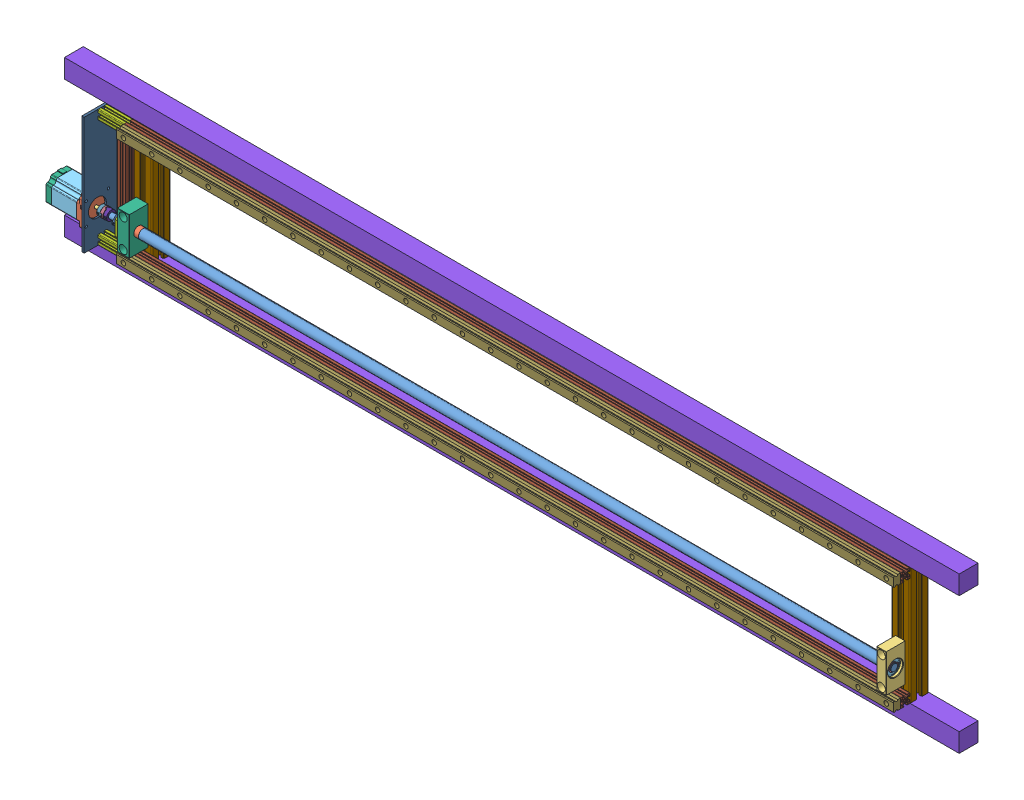
SolidWorks assembly bssc2010_1670_sc8_2_14b, configuration Standard. Lengths in mm.
Overall size (1900 330 89.2).
42 component instances, 29 part files, 49 mates.
Components (placement in the parent):
- y.1-1: y.1 [Standard] at (-1937.1438 -828.3671 5594.6293) x (-1 0 0) z (0 -0.561643 0.82738) size (1670 20 20)
- y.3-1: y.3 [Standard] at (-1937.1438 -828.3671 5594.6293) x (-1 0 0) z (0 0.924225 0.381849) size (15 20 20)
- buv15_2_14b-1: buv15_2_14b [Standard] at (-1954.6438 -828.3671 5594.6293) x (1 0 0) z (0 -1 0) size (20 41 80)
  - y.1.1.1-1: y.1.1.1 [Standard] at origin size (20 41 80)
  - y.2.1.1-1: y.2.1.1 [Standard] at (5 0 0) size (1 20 17.6)
  - y.3.1.1-1: y.3.1.1 [Standard] at origin size (9 32 32)
- bsv15_2_14b-1: bsv15_2_14b [Standard] at (-3542.1438 -828.3671 5594.6293) x (-1 0 0) z (0 1 0) size (43 41 80)
  - y.1.1-1: y.1.1 [Standard] at origin size (25 41 80)
  - y.2.1-1: y.2.1 [Standard] at origin size (8 37 37)
  - y.3.1-1: y.3.1 [Standard] at origin size (18 32 32)
  - y.4.1-1: y.4.1 [Standard] at origin size (10 20 20)
  - y.5.1-1: y.5.1 [Standard] at origin size (10 26.45 26.45)
- bosch_3842992888_e3htx9vi1mc72io2jozt5vwey-1: bosch_3842992888_e3htx9vi1mc72io2jozt5vwey [Default] at (-3574.6438 -658.3671 5583.6293) size (1650 20 20)
- bosch_3842992888_e3htx9vi1mc72io2jozt5vwey-2: bosch_3842992888_e3htx9vi1mc72io2jozt5vwey [Default] at (-3574.6438 -888.3671 5583.6293) size (1650 20 20)
- y.1.1.1.1-1: y.1.1.1.1 [Standard] at (-2749.6438 -888.3671 5593.6293) x (0 1 0) z (1 0 0) size (20 15.5 1650)
- y.1.1.1.1-2: y.1.1.1.1 [Standard] at (-2749.6438 -658.3671 5593.6293) x (0 -1 0) z (-1 0 0) size (20 15.5 1650)
- mco20_6_35_10_2_14b-1: mco20_6_35_10_2_14b [Standard] at (-3610.4438 -828.3671 5594.6293) size (21.4 21 21)
  - y.a-1: y.a [Standard] at origin size (6.6 21 21)
  - y.b-1: y.b [Standard] at origin size (10.2 20 20)
  - y.c-1: y.c [Standard] at origin size (4 4 5.1)
  - y.d-1: y.d [Standard] at origin size (4 5.1 4)
  - y.e-1: y.e [Standard] at origin size (10.2 20 20)
  - y.f-1: y.f [Standard] at origin size (4 5.1 4)
  - y.g-1: y.g [Standard] at origin size (4 4 5.1)
- ST5918L1008-1: ST5918L1008 [Standard] at (-3639.0438 -828.3671 5594.6293) x (0 0 -1) z (1 0 0) size (56.4 58.1 96.6)
  - Frontcap_ST5918-1: Frontcap_ST5918 [Standard] at (0 0 -6.3) size (56.4 56.4 12.6)
  - shaft_forward_5709-1: shaft_forward_5709 [Standard] at (0 0 25.3) x (1 0 0) z (0 0 -1) size (6.35 6.35 19)
  - Schrauben_ISO_7045_M3-1: Schrauben_ISO_7045_M3 [Standard] at (-11.2 -25.35 2.2) x (0 1 0) z (1 0 0) size (5.57 2.46 5.76)
  - Schrauben_ISO_7045_M3-2: Schrauben_ISO_7045_M3 [Standard] at (25.35 -11.2 2.2) x (1 0 0) z (0 -1 0) size (5.57 2.46 5.76)
  - Schrauben_ISO_7045_M3-3: Schrauben_ISO_7045_M3 [Standard] at (11.2 25.35 2.2) x (1 0 0) z (0 -1 0) size (5.57 2.46 5.76)
  - Schrauben_ISO_7045_M3-4: Schrauben_ISO_7045_M3 [Standard] at (-25.35 11.2 2.2) x (1 0 0) z (0 -1 0) size (5.57 2.46 5.76)
  - Stator_5918_L-1: Stator_5918_L [Standard] at (0 0 -6.3) x (1 0 0) z (0 0 -1) size (56.4 56.4 53)
  - Endcap ST5918_kompl-1: Endcap ST5918_kompl [Standard] at (0 0.85 -65.3) x (1 0 0) z (0 0 -1) size (56.4 58.1 12)
    - Endcap_5918-1: Endcap_5918 [Standard] at (0 0.85 -6) size (56.4 58.1 12)
- bosch_3842992888_aff6iaz91xwbgzhnykkapvmd0-1: bosch_3842992888_aff6iaz91xwbgzhnykkapvmd0 [Default] at (-3631.3438 -888.3671 5583.6293) size (54.7 20 20)
- bosch_3842992888_aff6iaz91xwbgzhnykkapvmd0-2: bosch_3842992888_aff6iaz91xwbgzhnykkapvmd0 [Default] at (-3631.3438 -658.3671 5583.6293) size (54.7 20 20)
- bosch_3842993120_2dhdbkbtd5fyfxp6933e5ukc1-1: bosch_3842993120_2dhdbkbtd5fyfxp6933e5ukc1 [Default] at (-1820.3438 -628.3671 5553.6293) x (-1 0 0) z (0 -1 0) size (1900 40 40)
- bosch_3842993120_2dhdbkbtd5fyfxp6933e5ukc1-2: bosch_3842993120_2dhdbkbtd5fyfxp6933e5ukc1 [Default] at (-3720.3438 -918.3671 5553.6293) size (1900 40 40)
- bosch_3842993120_eumn6jp9o5yoh0dwa8a7bcaxi-1: bosch_3842993120_eumn6jp9o5yoh0dwa8a7bcaxi [Default] at (-1944.6438 -898.3671 5553.6293) x (0 1 0) z (0 0 1) size (250 40 40)
- bosch_3842993120_eumn6jp9o5yoh0dwa8a7bcaxi-2: bosch_3842993120_eumn6jp9o5yoh0dwa8a7bcaxi [Default] at (-3554.6438 -898.3671 5553.6293) x (0 1 0) z (0 0 1) size (250 40 40)
- Halterung_rechts-1: Halterung_rechts [Standard] at (-3634.3438 -898.3671 5533.6293) x (0 1 0) z (1 0 0) size (250 89.2 5)
- bosch_3842992888_dkjhmsmcdl964fh57wefn4aov-1: bosch_3842992888_dkjhmsmcdl964fh57wefn4aov [Default] at (-3619.3438 -898.3671 5543.6293) x (0 1 0) z (0 0 1) size (250 20 20)
Mates (geometry in assembly coordinates):
- Konzentrisch1: concentric aligned: cylinder of y.1-1 through (-3559.5438 -828.3671 5594.6293) axis (-1 0 0) radius 7.5; cylinder of y.3-1 through (-3539.6438 -828.3671 5594.6293) axis (-1 0 0) radius 7.5
- Deckungsgleich1: coincident anti-aligned: plane of y.1-1 through (-3532.1438 -835.7308 5589.6307) normal (-1 0 0); plane of y.3-1 through (-3532.1438 -831.7656 5602.8549) normal (1 0 0)
- Konzentrisch3: concentric aligned: cylinder of y.1-1 through (-1944.4938 -828.3671 5594.6293) axis (-1 0 0) radius 7.5; cylinder of buv15_2_14b-1/y.3.1.1-1 through (-1944.6438 -828.3671 5594.6293) axis (-1 0 0) radius 7.5
- Deckungsgleich3: coincident anti-aligned: plane of y.1-1 through (-1949.1438 -835.5239 5589.7711) normal (1 0 0); plane of buv15_2_14b-1/y.3.1.1-1 through (-1949.1438 -828.3671 5585.9043) normal (-1 0 0)
- Deckungsgleich4: coincident anti-aligned: plane of y.3-1 through (-3547.1438 -831.7656 5602.8549) normal (-1 0 0); plane of bsv15_2_14b-1/y.3.1-1 through (-3547.1438 -828.3671 5586.0543) normal (1 0 0)
- Konzentrisch4: concentric anti-aligned: cylinder of y.1-1 through (-3559.5438 -828.3671 5594.6293) axis (-1 0 0) radius 7.5; cylinder of bsv15_2_14b-1/y.3.1-1 through (-3551.5688 -828.3671 5594.6293) axis (1 0 0) radius 7.5
- Deckungsgleich5: coincident aligned: plane of buv15_2_14b-1/y.1.1.1-1 through (-1935.1438 -868.3671 5614.6293) normal (0 0 1); plane of bsv15_2_14b-1/y.1.1-1 through (-3566.6438 -788.3671 5614.6293) normal (0 0 1)
- Deckungsgleich18: coincident anti-aligned: plane of bosch_3842992888_e3htx9vi1mc72io2jozt5vwey-2 through (-3574.6438 -884.8671 5593.6293) normal (0 0 1); plane of y.1.1.1.1-1 through (-1924.6438 -898.3671 5593.6293) normal (0 0 -1)
- Deckungsgleich19: coincident aligned: plane of bosch_3842992888_e3htx9vi1mc72io2jozt5vwey-2 through (-1924.6438 -888.3671 5583.6293) normal (1 0 0); plane of y.1.1.1.1-1 through (-1924.6438 -888.3671 5593.6293) normal (1 0 0)
- Deckungsgleich20: coincident aligned: plane of bosch_3842992888_e3htx9vi1mc72io2jozt5vwey-2 through (-3574.6438 -898.3671 5587.1293) normal (0 -1 0); plane of y.1.1.1.1-1 through (-1924.6438 -898.3671 5599.8093) normal (0 -1 0)
- Deckungsgleich21: coincident anti-aligned: plane of bosch_3842992888_e3htx9vi1mc72io2jozt5vwey-1 through (-3574.6438 -654.8671 5593.6293) normal (0 0 1); plane of y.1.1.1.1-2 through (-3574.6438 -648.3671 5593.6293) normal (0 0 -1)
- Deckungsgleich22: coincident aligned: plane of bosch_3842992888_e3htx9vi1mc72io2jozt5vwey-1 through (-3574.6438 -658.3671 5583.6293) normal (-1 0 0); plane of y.1.1.1.1-2 through (-3574.6438 -658.3671 5593.6293) normal (-1 0 0)
- Deckungsgleich23: coincident aligned: plane of bosch_3842992888_e3htx9vi1mc72io2jozt5vwey-1 through (-3574.6438 -668.3671 5587.1293) normal (0 -1 0); plane of y.1.1.1.1-2 through (-3574.6438 -668.3671 5593.6293) normal (0 -1 0)
- Konzentrisch6: concentric aligned: cylinder of y.1-1 through (-3596.8938 -828.3671 5594.6293) axis (-1 0 0) radius 6; cylinder of mco20_6_35_10_2_14b-1/y.e-1 through (-3604.8438 -828.3671 5594.6293) axis (-1 0 0) radius 5
- Deckungsgleich40: coincident anti-aligned: plane of y.1-1 through (-3607.1438 -830.6424 5593.0848) normal (-1 0 0); plane of mco20_6_35_10_2_14b-1/y.a-1 through (-3607.1438 -828.3671 5587.3293) normal (1 0 0)
- Konzentrisch7: concentric anti-aligned: cylinder of mco20_6_35_10_2_14b-1/y.b-1 through (-3616.0438 -828.3671 5594.6293) axis (1 0 0) radius 3.175; cylinder of ST5918L1008-1/shaft_forward_5709-1 through (-3613.7438 -828.3671 5594.6293) axis (-1 0 0) radius 3.175
- Deckungsgleich42: coincident anti-aligned: plane of mco20_6_35_10_2_14b-1/y.a-1 through (-3613.7438 -828.3671 5587.3293) normal (-1 0 0); plane of ST5918L1008-1/shaft_forward_5709-1 through (-3613.7438 -828.3671 5594.6293) normal (1 0 0)
- Deckungsgleich43: coincident anti-aligned: plane of bosch_3842992888_e3htx9vi1mc72io2jozt5vwey-2 through (-3574.6438 -888.3671 5583.6293) normal (-1 0 0); plane of bosch_3842992888_aff6iaz91xwbgzhnykkapvmd0-1 through (-3574.6438 -888.3671 5583.6293) normal (1 0 0)
- Deckungsgleich44: coincident aligned: plane of bosch_3842992888_e3htx9vi1mc72io2jozt5vwey-2 through (-3574.6438 -898.3671 5587.1293) normal (0 -1 0); plane of bosch_3842992888_aff6iaz91xwbgzhnykkapvmd0-1 through (-3631.3438 -898.3671 5587.1293) normal (0 -1 0)
- Deckungsgleich45: coincident aligned: plane of bosch_3842992888_e3htx9vi1mc72io2jozt5vwey-2 through (-3574.6438 -891.8671 5573.6293) normal (0 0 -1); plane of bosch_3842992888_aff6iaz91xwbgzhnykkapvmd0-1 through (-3631.3438 -891.8671 5573.6293) normal (0 0 -1)
- Deckungsgleich46: coincident anti-aligned: plane of bosch_3842992888_e3htx9vi1mc72io2jozt5vwey-1 through (-3574.6438 -658.3671 5583.6293) normal (-1 0 0); plane of bosch_3842992888_aff6iaz91xwbgzhnykkapvmd0-2 through (-3574.6438 -658.3671 5583.6293) normal (1 0 0)
- Deckungsgleich47: coincident aligned: plane of bosch_3842992888_e3htx9vi1mc72io2jozt5vwey-1 through (-3574.6438 -648.3671 5592.1293) normal (0 1 0); plane of bosch_3842992888_aff6iaz91xwbgzhnykkapvmd0-2 through (-3631.3438 -648.3671 5592.1293) normal (0 1 0)
- Deckungsgleich48: coincident aligned: plane of bosch_3842992888_e3htx9vi1mc72io2jozt5vwey-1 through (-3574.6438 -649.8671 5573.6293) normal (0 0 -1); plane of bosch_3842992888_aff6iaz91xwbgzhnykkapvmd0-2 through (-3631.3438 -649.8671 5573.6293) normal (0 0 -1)
- Abstand17: distance = 10 mm anti-aligned: plane of bsv15_2_14b-1/y.1.1-1 through (-3542.1438 -868.3671 5594.6293) normal (0 -1 0); plane of bosch_3842992888_e3htx9vi1mc72io2jozt5vwey-2 through (-3574.6438 -878.3671 5592.1293) normal (0 1 0)
- Deckungsgleich66: coincident anti-aligned: plane of bosch_3842992888_aff6iaz91xwbgzhnykkapvmd0-1 through (-3631.3438 -898.3671 5587.1293) normal (0 -1 0); plane of bosch_3842993120_2dhdbkbtd5fyfxp6933e5ukc1-2 through (-2770.3438 -898.3671 5553.6293) normal (0 1 0)
- Parallel1: parallel aligned: plane of bosch_3842993120_2dhdbkbtd5fyfxp6933e5ukc1-1 through (-1820.3438 -628.3671 5553.6293) normal (1 0 0); plane of bosch_3842993120_2dhdbkbtd5fyfxp6933e5ukc1-2 through (-1820.3438 -918.3671 5553.6293) normal (1 0 0)
- Parallel2: parallel aligned: plane of bosch_3842993120_2dhdbkbtd5fyfxp6933e5ukc1-1 through (-3720.3438 -628.3671 5553.6293) normal (-1 0 0); plane of bosch_3842993120_2dhdbkbtd5fyfxp6933e5ukc1-2 through (-3720.3438 -918.3671 5553.6293) normal (-1 0 0)
- Deckungsgleich77: coincident aligned: plane of bosch_3842993120_2dhdbkbtd5fyfxp6933e5ukc1-1 through (-3720.3438 -628.3671 5553.6293) normal (-1 0 0); plane of bosch_3842993120_2dhdbkbtd5fyfxp6933e5ukc1-2 through (-3720.3438 -918.3671 5553.6293) normal (-1 0 0)
- Deckungsgleich80: coincident anti-aligned: plane of bosch_3842992888_aff6iaz91xwbgzhnykkapvmd0-2 through (-3631.3438 -648.3671 5580.1293) normal (0 1 0); plane of bosch_3842993120_2dhdbkbtd5fyfxp6933e5ukc1-1 through (-2770.3438 -648.3671 5553.6293) normal (0 -1 0)
- Deckungsgleich83: coincident anti-aligned: plane of bosch_3842992888_aff6iaz91xwbgzhnykkapvmd0-1 through (-3631.3438 -891.8671 5573.6293) normal (0 0 -1); plane of bosch_3842993120_2dhdbkbtd5fyfxp6933e5ukc1-2 through (-2770.3438 -918.3671 5573.6293) normal (0 0 1)
- Deckungsgleich84: coincident aligned: plane of bosch_3842993120_2dhdbkbtd5fyfxp6933e5ukc1-1 through (-2770.3438 -628.3671 5573.6293) normal (0 0 1); plane of bosch_3842993120_2dhdbkbtd5fyfxp6933e5ukc1-2 through (-2770.3438 -918.3671 5573.6293) normal (0 0 1)
- Deckungsgleich86: coincident anti-aligned: plane of bosch_3842992888_aff6iaz91xwbgzhnykkapvmd0-2 through (-3631.3438 -661.8671 5573.6293) normal (0 0 -1); plane of bosch_3842993120_2dhdbkbtd5fyfxp6933e5ukc1-1 through (-2770.3438 -628.3671 5573.6293) normal (0 0 1)
- Deckungsgleich106: coincident anti-aligned: plane of bosch_3842993120_2dhdbkbtd5fyfxp6933e5ukc1-1 through (-2770.3438 -648.3671 5553.6293) normal (0 -1 0); plane of bosch_3842993120_eumn6jp9o5yoh0dwa8a7bcaxi-1 through (-1944.6438 -648.3671 5553.6293) normal (0 1 0)
- Deckungsgleich107: coincident aligned: plane of bosch_3842993120_2dhdbkbtd5fyfxp6933e5ukc1-1 through (-2770.3438 -628.3671 5573.6293) normal (0 0 1); plane of bosch_3842993120_eumn6jp9o5yoh0dwa8a7bcaxi-1 through (-1927.6438 -898.3671 5573.6293) normal (0 0 1)
- Deckungsgleich108: coincident anti-aligned: plane of bosch_3842993120_2dhdbkbtd5fyfxp6933e5ukc1-1 through (-2770.3438 -648.3671 5553.6293) normal (0 -1 0); plane of bosch_3842993120_eumn6jp9o5yoh0dwa8a7bcaxi-2 through (-3554.6438 -648.3671 5553.6293) normal (0 1 0)
- Deckungsgleich109: coincident aligned: plane of bosch_3842993120_2dhdbkbtd5fyfxp6933e5ukc1-1 through (-2770.3438 -628.3671 5573.6293) normal (0 0 1); plane of bosch_3842993120_eumn6jp9o5yoh0dwa8a7bcaxi-2 through (-3537.6438 -898.3671 5573.6293) normal (0 0 1)
- Deckungsgleich110: coincident anti-aligned: plane of bsv15_2_14b-1/y.1.1-1 through (-3542.6438 -788.3671 5573.6293) normal (0 0 -1); plane of bosch_3842993120_eumn6jp9o5yoh0dwa8a7bcaxi-2 through (-3560.4438 -898.3671 5573.6293) normal (0 0 1)
- Abstand18: distance = 7.5 mm aligned: plane of bsv15_2_14b-1/y.1.1-1 through (-3567.1438 -788.3671 5574.1293) normal (-1 0 0); plane of bosch_3842993120_eumn6jp9o5yoh0dwa8a7bcaxi-2 through (-3574.6438 -898.3671 5570.6293) normal (-1 0 0)
- Abstand19: distance = 104.3 mm aligned: plane of bosch_3842993120_2dhdbkbtd5fyfxp6933e5ukc1-1 through (-1820.3438 -628.3671 5553.6293) normal (1 0 0); plane of bosch_3842993120_eumn6jp9o5yoh0dwa8a7bcaxi-1 through (-1924.6438 -898.3671 5559.4293) normal (1 0 0)
- Deckungsgleich113: coincident aligned: plane of bosch_3842992888_e3htx9vi1mc72io2jozt5vwey-1 through (-1924.6438 -658.3671 5583.6293) normal (1 0 0); plane of bosch_3842993120_eumn6jp9o5yoh0dwa8a7bcaxi-1 through (-1924.6438 -898.3671 5536.6293) normal (1 0 0)
- Deckungsgleich114: coincident anti-aligned: plane of bosch_3842993120_2dhdbkbtd5fyfxp6933e5ukc1-2 through (-2770.3438 -898.3671 5553.6293) normal (0 1 0); plane of bosch_3842993120_eumn6jp9o5yoh0dwa8a7bcaxi-1 through (-1944.6438 -898.3671 5553.6293) normal (0 -1 0)
- Abstand20: distance = 10 mm aligned: plane of buv15_2_14b-1/y.1.1.1-1 through (-1934.6438 -868.3671 5574.1293) normal (1 0 0); plane of bosch_3842993120_eumn6jp9o5yoh0dwa8a7bcaxi-1 through (-1924.6438 -898.3671 5559.4293) normal (1 0 0)
- Deckungsgleich127: coincident anti-aligned: plane of bosch_3842993120_2dhdbkbtd5fyfxp6933e5ukc1-2 through (-2770.3438 -898.3671 5553.6293) normal (0 1 0); plane of Halterung_rechts-1 through (-3629.3438 -898.3671 5533.6293) normal (0 -1 0)
- Deckungsgleich128: coincident anti-aligned: plane of bosch_3842993120_2dhdbkbtd5fyfxp6933e5ukc1-1 through (-2770.3438 -648.3671 5553.6293) normal (0 -1 0); plane of bosch_3842992888_dkjhmsmcdl964fh57wefn4aov-1 through (-3619.3438 -648.3671 5543.6293) normal (0 1 0)
- Deckungsgleich129: coincident aligned: plane of bosch_3842993120_2dhdbkbtd5fyfxp6933e5ukc1-1 through (-2770.3438 -628.3671 5533.6293) normal (0 0 -1); plane of bosch_3842992888_dkjhmsmcdl964fh57wefn4aov-1 through (-3615.8438 -898.3671 5533.6293) normal (0 0 -1)
- Abstand21: distance = 5 mm anti-aligned: plane of bosch_3842992888_dkjhmsmcdl964fh57wefn4aov-1 through (-3629.3438 -898.3671 5552.1293) normal (-1 0 0); plane of ST5918L1008-1/Frontcap_ST5918-1 through (-3634.3438 -828.3671 5594.6293) normal (1 0 0)
- Deckungsgleich132: coincident aligned: plane of ST5918L1008-1/Frontcap_ST5918-1 through (-3645.3438 -856.5671 5622.8293) normal (0 0 1); plane of Halterung_rechts-1 through (-3629.3438 -898.3671 5622.8293) normal (0 0 1)
- Deckungsgleich133: coincident anti-aligned: plane of bosch_3842992888_aff6iaz91xwbgzhnykkapvmd0-2 through (-3629.3438 -658.3671 5583.6293) normal (-1 0 0); plane of Halterung_rechts-1 through (-3629.3438 -898.3671 5533.6293) normal (1 0 0)
- Deckungsgleich134: coincident anti-aligned: plane of bosch_3842992888_aff6iaz91xwbgzhnykkapvmd0-1 through (-3629.3438 -888.3671 5583.6293) normal (-1 0 0); plane of Halterung_rechts-1 through (-3629.3438 -898.3671 5533.6293) normal (1 0 0)
